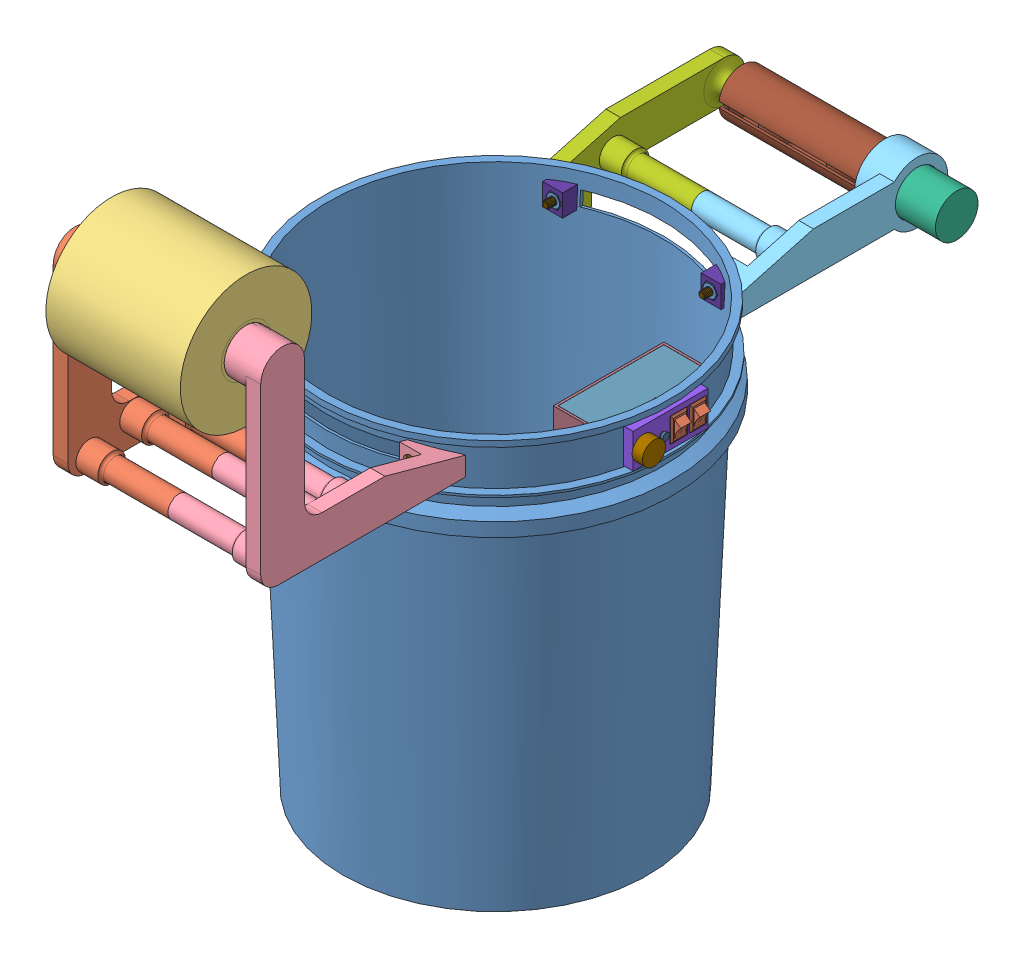
SolidWorks assembly Poop Bucket Assembly, configuration Default. Lengths in mm.
Overall size (317.61 555.84 638.39).
32 component instances, 20 part files, 62 mates.
Components (placement in the parent):
- Bucket-1: Bucket [Default] at (78.5579 50.5817 284.8963) size (309.6 368.3 309.6)
- Male Paper Holder-1: Male Paper Holder [Male] at (1.0879 387.3847 401.2505) x (0 0 1) z (-1 0 0) size (177.8 177.8 100.46)
- Toilet Paper-1: Toilet Paper [Default] at (136.9779 546.1347 560.0005) x (0 0.998401 -0.05652) z (0 0.05652 0.998401) size (114.3 116.84 114.3)
- Female Paper Holder-1: Female Paper Holder [Female] at (0.8339 387.3847 401.2505) x (0 0 1) z (-1 0 0) size (177.8 177.8 90.3)
- Male Paper Roller-1: Male Paper Roller [Male] at (156.0279 387.3847 168.5422) x (0 0 -1) z (1 0 0) size (186.64 53.24 100.33)
- DC Motor-1: DC Motor [Default] at (203.1279 405.1647 8.5222) x (0 0 1) z (0 -1 0) size (37 73.8 37)
- Female Paper Roller-1: Female Paper Roller [Female] at (156.0279 387.3847 168.5422) x (0 0 -1) z (1 0 0) size (177.8 35.56 90.17)
- Button Panel-1: Button Panel [Default] at (78.5579 380.9503 284.8963) size (17 30 65)
- Knob-1: Knob [Default] at (223.3697 395.9503 309.8463) x (0 0.366236 0.930522) z (0 0.930522 -0.366236) size (20 18 20)
- Button-1: Button [Default] at (232.3457 395.9503 292.1963) x (0 1 0) z (0 0 -1) size (6 8 6)
- Roll Tightener-3: Roll Tightener [Male] at (138.3279 405.1647 8.5222) x (0 0 -1) z (1 0 0) size (39.69 36.1 121.92)
- Roll Tightener-4: Roll Tightener [Female] at (16.4079 405.1647 8.5222) x (0 0 -1) z (-1 0 0) size (39.69 26 121.92)
- PCB Holder-1: PCB Holder [Default] at (201.1404 381.5503 325.0563) x (0 0 -1) z (1 0 0) size (91.72 11.16 23.8)
- Compartment-2: Compartment [Default] at (176.9404 345.0503 332.8963) size (52.37 66.02 96.02)
- Cover-1: Cover [Default] at origin size (42.13 4 91.8)
- LiPo-1: LiPo [Default] at (179.4404 362.0503 270.2963) x (0 0 -1) z (0 -1 0) size (52 21 30)
- Spring-1: Spring [Default] at (47.8879 411.1647 8.5222) x (0 0 1) z (1 0 0) size (22.74 21.49 22.74)
- Spring-3: Spring [Default] at (106.8479 411.1647 8.5222) x (0 0 1) z (1 0 0) size (22.74 21.49 22.74)
- Nut Holder-1: Nut Holder [Default] at (78.5579 389.5783 284.8963) size (17.27 19.05 13.64)
- 0.25in - 20 Screw-1: 0.25in - 20 Screw [90604A545] at (146.5029 399.1033 173.6222) x (0.364228 0.93131 0) z (0 0 -1) size (12.5 12.5 30.24)
- 0.25in - 20 Nut-1: 0.25in - 20 Nut [95505A601] at (146.5029 399.1033 164.0019) x (0.866025 -0.5 0) z (0 0 1) size (11.11 12.83 7.14)
- 0.25in - 20 Screw-3: 0.25in - 20 Screw [90604A545] at (10.6129 399.1033 173.6222) x (0.211959 0.977279 0) z (0 0 -1) size (12.5 12.5 30.24)
- Nut Holder-5: Nut Holder [Default] at (78.5579 408.6283 284.8963) x (-1 0 0) z (0 0 1) size (17.27 19.05 13.64)
- 0.25in - 20 Nut-3: 0.25in - 20 Nut [95505A601] at (10.6129 399.1033 164.0019) x (-0.866025 0.5 0) z (0 0 1) size (11.11 12.83 7.14)
- 0.25in - 20 Screw-5: 0.25in - 20 Screw [90604A545] at (146.5029 399.1033 396.1705) x (0.364228 0.93131 0) z (0 0 1) size (12.5 12.5 30.24)
- 0.25in - 20 Nut-5: 0.25in - 20 Nut [95505A601] at (146.5029 399.1033 405.7898) x (0.866025 -0.5 0) z (0 0 1) size (11.11 12.83 7.14)
- Nut Holder-7: Nut Holder [Default] at (78.5579 408.6283 284.8963) x (1 0 0) z (0 0 -1) size (17.27 19.05 13.64)
- 0.25in - 20 Nut-6: 0.25in - 20 Nut [95505A601] at (10.6129 399.1033 405.7898) x (-0.866025 0.5 0) z (0 0 1) size (11.11 12.83 7.14)
- 0.25in - 20 Screw-6: 0.25in - 20 Screw [90604A545] at (10.6129 399.1033 396.1705) x (-0.211959 -0.977279 0) z (0 0 1) size (12.5 12.5 30.24)
- Nut Holder-8: Nut Holder [Default] at (78.5579 389.5783 284.8963) x (-1 0 0) z (0 0 -1) size (17.27 19.05 13.64)
- Switch-1: Switch [Default] at (220.8457 395.9503 278.2463) x (0 -1 0) z (1 0 0) size (21 14.8 24.8)
- Switch-2: Switch [Default] at (220.8457 395.9503 261.4963) x (0 -1 0) z (1 0 0) size (21 14.8 24.8)
Mates (geometry in assembly coordinates):
- Concentric2: concentric: cone of Bucket-1 through (78.5579 50.5817 284.8963) axis (0 -1 0); cylinder of Male Paper Holder-1 through (78.5579 -26.4255 284.8963) axis (0 1 0) radius 146.304
- Coincident2: coincident: plane of Bucket-1 through (20.1379 405.0382 462.6963) normal (1 0 0); plane of Male Paper Holder-1 through (20.1379 355.6347 401.2505) normal (1 0 0)
- Concentric3: concentric: cylinder of Toilet Paper-1 through (20.1379 546.1347 560.0005) axis (1 0 0) radius 19.05; cylinder of Female Paper Holder-1 through (78.4309 546.1347 560.0005) axis (1 0 0) radius 12.7
- Distance1: distance = 8.89 mm: plane of Male Paper Holder-1 through (-11.6121 387.3847 401.2505) normal (0 -1 0); plane of Bucket-1 through (78.5579 378.4947 284.8963) normal (0 1 0)
- Concentric4: concentric: cone of Bucket-1 through (78.5579 378.4947 284.8963) axis (0 -1 0); cylinder of Female Paper Holder-1 through (78.5579 -26.4255 284.8963) axis (0 1 0) radius 146.304
- Concentric5: concentric: cylinder of Male Paper Holder-1 through (88.8449 399.5767 560.0005) axis (-1 0 0) radius 5.08; cylinder of Female Paper Holder-1 through (88.9909 399.5767 560.0005) axis (-1 0 0) radius 5.38
- Concentric6: concentric: cone of Bucket-1 through (78.5579 50.5817 284.8963) axis (0 -1 0); cylinder of Male Paper Roller-1 through (78.5579 352.2759 284.8963) axis (0 1 0) radius 146.304
- Coincident3: coincident: plane of Bucket-1 through (136.9779 405.0382 462.6963) normal (-1 0 0); plane of Male Paper Roller-1 through (136.9779 355.6347 168.5422) normal (-1 0 0)
- Distance2: distance = 8.89 mm: plane of Male Paper Roller-1 through (168.7279 387.3847 168.5422) normal (0 -1 0); plane of Bucket-1 through (78.5579 378.4947 284.8963) normal (0 1 0)
- Concentric7: concentric: cone of Bucket-1 through (78.5579 378.4947 284.8963) axis (0 -1 0); cylinder of Female Paper Roller-1 through (78.5579 352.2759 284.8963) axis (0 1 0) radius 146.304
- Coincident5: coincident: plane of Male Paper Roller-1 through (168.7279 422.9447 168.5422) normal (0 1 0); plane of Female Paper Roller-1 through (-11.6121 422.9447 168.5422) normal (0 1 0)
- Concentric8: concentric: cylinder of Male Paper Roller-1 through (143.3279 405.1647 8.5222) axis (1 0 0) radius 19; cylinder of DC Motor-1 through (143.3279 405.1647 8.5222) axis (1 0 0) radius 18.5
- Coincident8: coincident: plane of Male Paper Roller-1 through (143.3279 387.3847 168.5422) normal (1 0 0); plane of DC Motor-1 through (143.3279 405.1647 8.5222) normal (-1 0 0)
- Width1: width: plane of Toilet Paper-1 through (136.9779 546.1347 560.0005) normal (1 0 0); plane of Female Paper Holder-1 through (20.1379 546.1347 560.0005) normal (-1 0 0); plane of Toilet Paper-1 through (136.9779 355.6347 401.2505) normal (-1 0 0); plane of Male Paper Holder-1 through (20.1379 355.6347 401.2505) normal (1 0 0)
- Coincident9: coincident: plane of Bucket-1 through (233.3597 385.1503 253.7963) normal (0 1 0); plane of Button Panel-1 through (213.8457 385.1503 284.8963) normal (0 -1 0)
- Coincident10: coincident: plane of Bucket-1 through (233.3597 407.2503 315.9963) normal (0 0 -1); plane of Button Panel-1 through (213.8457 380.9503 315.9963) normal (0 0 1)
- Concentric10: concentric: cone of Bucket-1 through (78.5579 378.4947 284.8963) axis (0 -1 0); cylinder of Button Panel-1 through (78.5579 410.9503 284.8963) axis (0 -1 0) radius 147.415
- Concentric12: concentric: cylinder of Button Panel-1 through (190.1029 395.9503 309.8463) axis (1 0 0) radius 3.1; cylinder of Knob-1 through (232.3697 395.9503 309.8463) axis (-1 0 0) radius 2.95
- Distance3: distance = 1.524 mm: plane of Button Panel-1 through (230.8457 410.9503 284.8963) normal (1 0 0); plane of Knob-1 through (232.3697 395.9503 309.8463) normal (-1 0 0)
- Coincident17: coincident: plane of Bucket-1 through (20.1379 405.0382 462.6963) normal (1 0 0); plane of Female Paper Roller-1 through (20.1379 355.6347 168.5422) normal (1 0 0)
- Concentric19: concentric: cylinder of Female Paper Roller-1 through (34.1079 405.1647 8.5222) axis (-1 0 0) radius 6.35; cylinder of Roll Tightener-3 through (20.4079 405.1647 8.5222) axis (-1 0 0) radius 6.6
- Parallel4: parallel: plane of DC Motor-1 through (129.3279 407.6647 8.5222) normal (0 1 0); plane of Roll Tightener-3 through (128.3279 407.6647 8.5222) normal (0 -1 0)
- Concentric22: concentric: cylinder of Roll Tightener-3 through (16.4079 405.1647 8.5222) axis (1 0 0) radius 17.6; cylinder of Roll Tightener-4 through (138.3279 405.1647 8.5222) axis (-1 0 0) radius 17.6
- Coincident25: coincident: plane of DC Motor-1 through (138.3279 405.1647 8.5222) normal (-1 0 0); plane of Roll Tightener-3 through (138.3279 405.1647 8.5222) normal (1 0 0)
- Concentric23: concentric: cylinder of Roll Tightener-4 through (47.8879 411.1647 8.5222) axis (0 -1 0) radius 10.9; cylinder of Roll Tightener-3 through (47.8879 399.1647 8.5222) axis (0 1 0) radius 10.9
- Concentric25: concentric: circle of Bucket-1; circle of Compartment2-2
- Width2: width: plane of Compartment2-2 through (229.3003 384.8503 332.8963) normal (0 1 0); plane of Button Panel-1 through (229.3003 407.0503 332.8963) normal (0 -1 0); plane of Compartment2-2 through (213.8457 385.1503 284.8963) normal (0 -1 0); plane of Button Panel-1 through (213.8457 406.7503 284.8963) normal (0 1 0)
- Width3: width: plane of Compartment2-2 through (229.3003 345.0503 253.7463) normal (0 0 1); plane of Button Panel-1 through (229.3003 345.0503 316.0463) normal (0 0 -1); plane of Compartment2-2 through (213.8457 380.9503 253.7963) normal (0 0 -1); plane of Button Panel-1 through (213.8457 380.9503 315.9963) normal (0 0 1)
- Coincident27: coincident: plane of PCB Holder2-1 through (178.9404 380.5503 325.0563) normal (-1 0 0); plane of Compartment2-2 through (178.9404 345.0503 332.8963) normal (1 0 0)
- Coincident28: coincident: plane of PCB Holder2-1 through (201.1404 380.5503 238.8963) normal (0 0 -1); plane of Compartment2-2 through (176.9404 345.0503 238.8963) normal (0 0 1)
- Coincident29: coincident: plane of PCB Holder2-1 through (201.1404 380.5503 325.0563) normal (0 -1 0); plane of Compartment2-2 through (176.9404 380.5503 332.8963) normal (0 1 0)
- Concentric26: concentric: cylinder of Male Paper Roller-1 through (146.5029 399.1033 168.5432) axis (0 0 -1) radius 3.302; cylinder of Nut Holder-1 through (146.5029 399.1033 152.6652) axis (0 0 1) radius 3.556
- Concentric27: concentric: cone of Bucket-1 through (78.5579 418.8817 284.8963) axis (0 -1 0); cylinder of Nut Holder-1 through (78.5579 408.6283 284.8963) axis (0 -1 0) radius 145.288
- Concentric32: concentric: cylinder of Male Paper Roller-1 through (146.5029 399.1033 168.5432) axis (0 0 -1) radius 3.302; circle of 0.25in - 20 Screw-1
- Coincident30: coincident: plane of Male Paper Roller-1 through (146.5029 399.1033 148.2222) normal (0 0 -1); plane of 0.25in - 20 Screw-1 through (141.4288 401.0877 148.2222) normal (0 0 1)
- Concentric33: concentric: circle of Male Paper Roller-1; circle of 0.25in - 20 Nut-1
- Parallel5: parallel: plane of Nut Holder-1 through (138.7554 424.3334 161.2238) normal (-0.866025 -0.5 0); plane of 0.25in - 20 Nut-1 through (152.9187 399.1033 166.78) normal (0.866025 0.5 0)
- Coincident32: coincident: plane of Nut Holder-1 through (78.5579 389.5783 161.2238) normal (0 0 1); plane of 0.25in - 20 Nut-1 through (143.295 404.6596 161.2238) normal (0 0 -1)
- Parallel7: parallel: plane of Nut Holder-5 through (18.3603 373.8733 161.2238) normal (0.866025 0.5 0); plane of 0.25in - 20 Nut-3 through (4.1971 399.1033 166.78) normal (-0.866025 -0.5 0)
- Coincident35: coincident: plane of Nut Holder-5 through (78.5579 408.6283 161.2238) normal (0 0 1); plane of 0.25in - 20 Nut-3 through (13.8208 393.5471 161.2238) normal (0 0 -1)
- Concentric38: concentric: cylinder of Female Paper Roller-1 through (10.6129 399.1033 168.5432) axis (0 0 -1) radius 3.302; cylinder of Nut Holder-5 through (10.6129 399.1033 152.6652) axis (0 0 1) radius 3.556
- Concentric39: concentric: cone of Bucket-1 through (78.5579 418.8817 284.8963) axis (0 -1 0); cylinder of Nut Holder-5 through (78.5579 389.5783 284.8963) axis (0 1 0) radius 145.288
- Concentric40: concentric: cylinder of Female Paper Roller-1 through (10.6129 399.1033 148.2222) axis (0 0 -1) radius 6.35; circle of 0.25in - 20 Screw-3
- Coincident36: coincident: plane of Female Paper Roller-1 through (10.6129 399.1033 148.2222) normal (0 0 -1); plane of 0.25in - 20 Screw-3 through (5.2883 400.2581 148.2222) normal (0 0 1)
- Concentric41: concentric: circle of Female Paper Roller-1; circle of 0.25in - 20 Nut-3
- Width4: width: plane of Switch-1 through (230.8457 404.2503 272.4963) normal (0 0 -1); plane of Switch-1 through (230.8457 404.2503 283.9963) normal (0 0 1); plane of Button Panel-1 through (190.1029 380.9503 284.9463) normal (0 0 -1); plane of Button Panel-1 through (190.1029 380.9503 271.5463) normal (0 0 1)
- Coincident37: coincident: plane of Button Panel-1 through (230.8457 410.9503 284.8963) normal (1 0 0); plane of Switch-1 through (230.8457 395.9503 278.2463) normal (-1 0 0)
- Width5: width: plane of Switch-1 through (220.8457 405.0003 269.8863) normal (0 1 0); plane of Switch-1 through (220.8457 386.9003 269.8863) normal (0 -1 0); plane of Button Panel-1 through (190.1029 405.7503 284.8963) normal (0 -1 0); plane of Button Panel-1 through (190.1029 386.1503 284.8963) normal (0 1 0)
- Width6: width: plane of Switch-2 through (230.8457 404.2503 255.7463) normal (0 0 -1); plane of Switch-2 through (230.8457 404.2503 267.2463) normal (0 0 1); plane of Button Panel-1 through (190.1029 380.9503 254.7963) normal (0 0 1); plane of Button Panel-1 through (190.1029 380.9503 268.1963) normal (0 0 -1)
- Coincident38: coincident: plane of Button Panel-1 through (230.8457 410.9503 284.8963) normal (1 0 0); plane of Switch-2 through (230.8457 395.9503 261.4963) normal (-1 0 0)
- Width7: width: plane of Switch-2 through (220.8457 405.0003 253.1363) normal (0 1 0); plane of Switch-2 through (220.8457 386.9003 253.1363) normal (0 -1 0); plane of Button Panel-1 through (190.1029 405.7503 284.8963) normal (0 -1 0); plane of Button Panel-1 through (190.1029 386.1503 284.8963) normal (0 1 0)
- Concentric42: concentric: cylinder of Button Panel-1 through (190.1029 395.9503 292.1963) axis (1 0 0) radius 2.1; cylinder of Button-1 through (226.3457 395.9503 292.1963) axis (1 0 0) radius 1.8
- Distance4: distance = 1.5 mm: plane of Button-1 through (232.3457 395.9503 292.1963) normal (-1 0 0); plane of Button Panel-1 through (230.8457 410.9503 284.8963) normal (1 0 0)
- Coincident43: coincident: plane of Compartment-2 through (78.7133 347.0503 284.8963) normal (0 1 0); plane of LiPo-1 through (200.4404 347.0503 296.2963) normal (0 -1 0)
- Width9: width: plane of LiPo-1 through (200.4404 377.0503 296.2963) normal (0 0 1); plane of LiPo-1 through (200.4404 377.0503 244.2963) normal (0 0 -1); plane of Compartment-2 through (78.7133 380.5503 300.2963) normal (0 0 -1); plane of Compartment-2 through (176.9404 383.2429 240.2963) normal (0 0 1)
- Width10: width: plane of LiPo-1 through (179.4404 362.0503 270.2963) normal (-1 0 0); plane of LiPo-1 through (200.4404 362.0503 270.2963) normal (1 0 0); plane of Compartment-2 through (178.9404 345.0503 332.8963) normal (1 0 0); plane of Compartment-2 through (200.9404 380.5503 284.8963) normal (-1 0 0)
- Coincident44: coincident: line of Roll Tightener-4 through (47.8879 411.1647 8.5222) axis (0 -1 0); line of Spring-1 through (47.8879 389.3458 8.5222) axis (0 1 0)
- Coincident45: coincident: plane of Roll Tightener-4 through (16.4079 411.1647 8.5222) normal (0 1 0); plane of Spring-1 through (47.8879 411.1647 8.5222) normal (0 -1 0)
- Coincident46: coincident: plane of Roll Tightener-4 through (47.8879 405.1647 8.5222) normal (1 0 0); plane of Spring-1 through (47.8879 411.1647 8.5222) normal (1 0 0)
- Coincident47: coincident: line of Roll Tightener-4 through (106.8479 411.1647 8.5222) axis (0 -1 0); line of Spring-3 through (106.8479 389.3458 8.5222) axis (0 1 0)
- Coincident48: coincident: plane of Roll Tightener-4 through (16.4079 411.1647 8.5222) normal (0 1 0); plane of Spring-3 through (106.8479 411.1647 8.5222) normal (0 -1 0)
- Coincident49: coincident: plane of Roll Tightener-4 through (106.8479 405.1647 8.5222) normal (1 0 0); plane of Spring-3 through (106.8479 411.1647 8.5222) normal (1 0 0)
